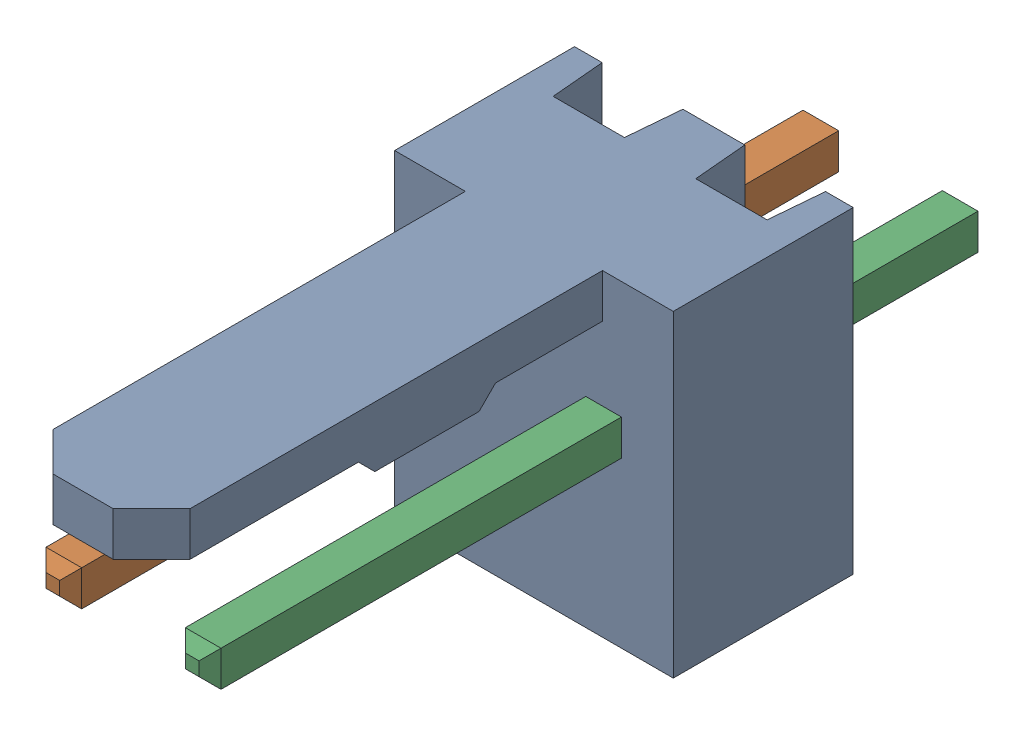
SolidWorks assembly Molex PCB 2 pin v2_2, configuration Default. Lengths in mm.
Overall size (5.08 5.79 14.92).
3 component instances, 2 part files, 0 mates.
Components (placement in the parent):
- BASE9710016_1-1: BASE9710016_1 [Default] at (2.54 2.895 -8.22) size (5.08 5.79 11.5)
- PINO9710016_1-1: PINO9710016_1 [Default] at (1.27 3.325 -0.72) size (0.65 0.65 14.2)
- PINO9710016_1-2: PINO9710016_1 [Default] at (3.81 3.325 -0.72) size (0.65 0.65 14.2)
